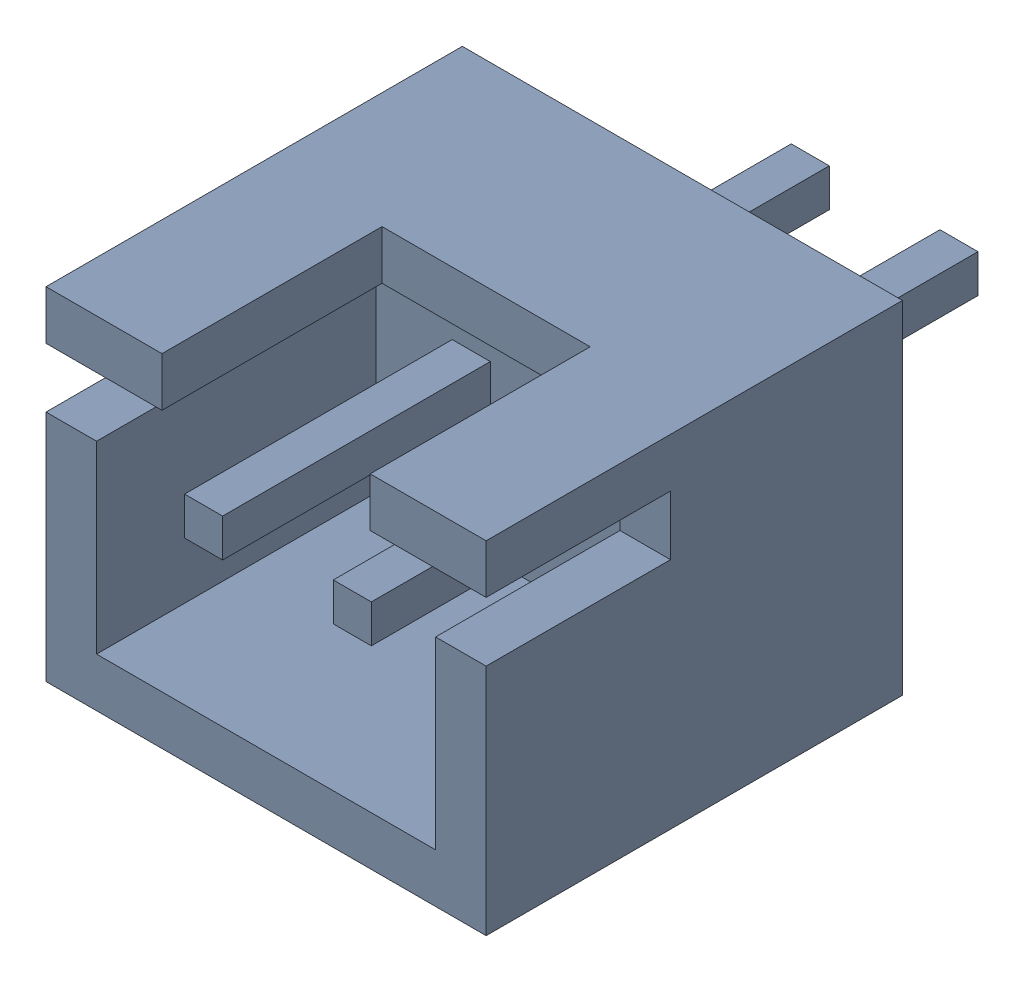
SolidWorks assembly BAT, configuration Défaut. Lengths in mm.
Overall size (7.4 5.75 10.4).
2 component instances, 1 part files, 0 mates.
Components (placement in the parent):
- Open CASCADE STEP translator 6.8 1.29.1-1: Open CASCADE STEP translator 6.8 1.29.1 [Défaut] at origin size (7.4 5.75 10.4)
  - Body_1_14-1: Body_1_14 [Défaut] at (-1.25 -0.5 0) x (-1 0 0) z (0 1 0) size (7.4 10.4 5.75)
